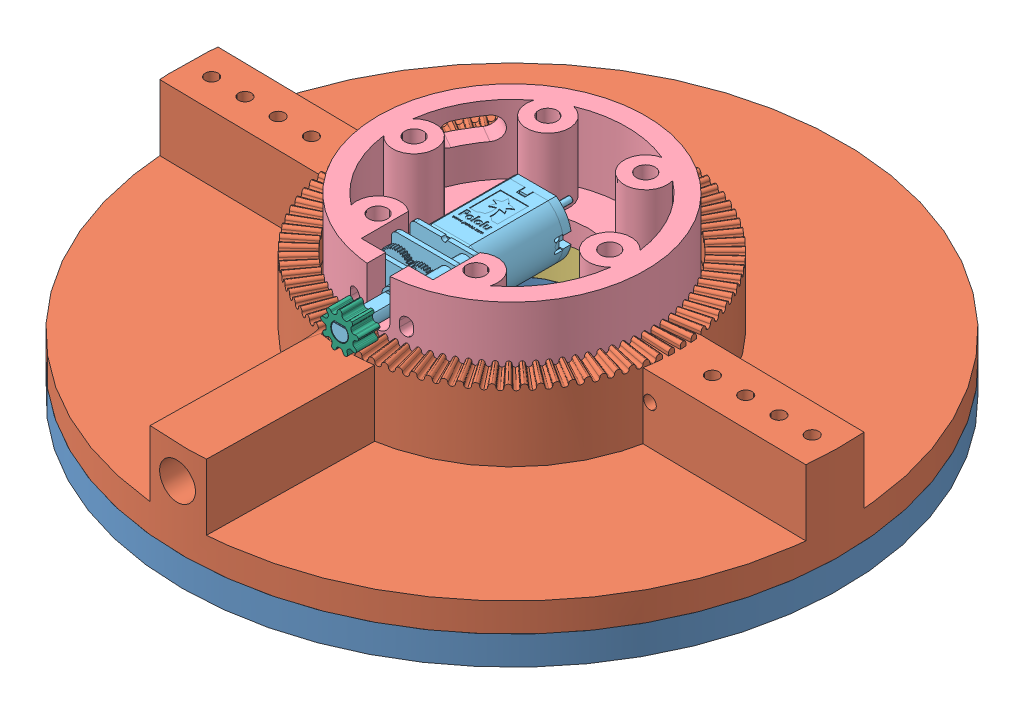
SolidWorks assembly new_assem, configuration Default. Lengths in mm.
Overall size (116.84 31 116.84).
6 component instances, 6 part files, 13 mates.
Components (placement in the parent):
- lower_platter-1: lower_platter [Default] at (-7.5252 -0.5831 4.7068) size (115 9 115)
- upper_platter-1: upper_platter [Default] at (-7.5252 15.9169 4.7068) x (0.99987 0 0.016145) z (0 -1 0) size (115 115 17.53)
- lower_platter_splitter-1: lower_platter_splitter [Default] at (-7.5252 9.4169 4.7068) x (1 0 0.000905) z (0 -1 0) size (46.67 46.67 6)
- lower_platter_closeout-1: lower_platter_closeout [Default] at (-7.5252 12.9169 4.7068) x (1 0 0.000905) z (0 -1 0) size (46.67 46.67 16)
- pololu_micro_motor-1: pololu_micro_motor [Default] at (-7.5351 19.4169 15.7068) x (1 0 0.000905) z (-0.000905 0 1) size (12.01 10.08 40.2)
- lil_gear-1: lil_gear [Default] at (-7.549 19.4169 30.9948) x (1 0 0.000905) z (-0.000905 0 1) size (6.61 6.52 3.75)
Mates (geometry in assembly coordinates):
- Concentric1: concentric anti-aligned: cylinder of lower_platter-1 through (-7.5252 -5.5831 4.7068) axis (0 1 0) radius 57.5; cylinder of upper_platter-1 through (-7.5252 4.4169 4.7068) axis (0 -1 0) radius 57.5
- Coincident1: coincident anti-aligned: plane of lower_platter-1 through (-7.5252 -0.5831 4.7068) normal (0 1 0); plane of upper_platter-1 through (-7.5252 -0.5831 4.7068) normal (0 -1 0)
- Coincident2: coincident anti-aligned: plane of lower_platter-1 through (-7.5252 3.4169 4.7068) normal (0 1 0); plane of lower_platter_splitter-1 through (-7.5252 3.4169 4.7068) normal (0 -1 0)
- Concentric2: concentric anti-aligned: cylinder of lower_platter-1 through (-7.5252 3.4169 4.7068) axis (0 -1 0) radius 13.335; cylinder of lower_platter_splitter-1 through (-7.5252 3.4169 4.7068) axis (0 1 0) radius 13.335
- Coincident3: coincident anti-aligned: plane of lower_platter_splitter-1 through (-7.5252 9.4169 4.7068) normal (0 1 0); plane of lower_platter_closeout-1 through (-7.5252 9.4169 4.7068) normal (0 -1 0)
- Concentric3: concentric aligned: cylinder of lower_platter_splitter-1 through (-7.5252 3.4169 4.7068) axis (0 1 0) radius 13.335; cylinder of lower_platter_closeout-1 through (-7.5252 9.4169 4.7068) axis (0 1 0) radius 13.335
- Concentric4: concentric aligned: cylinder of lower_platter_splitter-1 through (-24.6102 3.4169 4.6913) axis (0 1 0) radius 1.625; cylinder of lower_platter_closeout-1 through (-24.6102 25.4169 4.6913) axis (0 1 0) radius 1.625
- Parallel1: parallel aligned: cylinder of lower_platter-1 through (-24.6102 -5.5831 4.7068) axis (0 1 0) radius 1.625; cylinder of lower_platter_splitter-1 through (-24.6102 3.4169 4.6913) axis (0 1 0) radius 1.625
- Coincident4: coincident anti-aligned: plane of lower_platter_closeout-1 through (-7.5433 12.9169 24.7068) normal (0.000905 0 -1); plane of pololu_micro_motor-1 through (-13.5433 24.4169 24.7014) normal (-0.000905 0 1)
- Concentric8: concentric anti-aligned: cylinder of pololu_micro_motor-1 through (-7.5474 19.4169 29.2318) axis (-0.000905 0 1) radius 1.5; cylinder of lil_gear-1 through (-7.5523 19.4169 34.7448) axis (0.000905 0 -1) radius 1.55
- Parallel2: parallel anti-aligned: plane of pololu_micro_motor-1 through (-8.6703 20.4169 34.7058) normal (0 1 0); plane of lil_gear-1 through (-8.4705 20.6669 36.6014) normal (0 -1 0)
- Concentric9: concentric aligned: cylinder of lower_platter_closeout-1 through (-12.0463 19.4169 28.0377) axis (0.000905 0 -1) radius 1; cylinder of pololu_micro_motor-1 through (-12.0429 19.4169 24.3027) axis (0.000905 0 -1) radius 0.8
- Concentric10: concentric aligned: cylinder of lower_platter_closeout-1 through (-3.0463 19.4169 28.0459) axis (0.000905 0 -1) radius 1; cylinder of pololu_micro_motor-1 through (-3.0429 19.4169 24.3109) axis (0.000905 0 -1) radius 0.8
